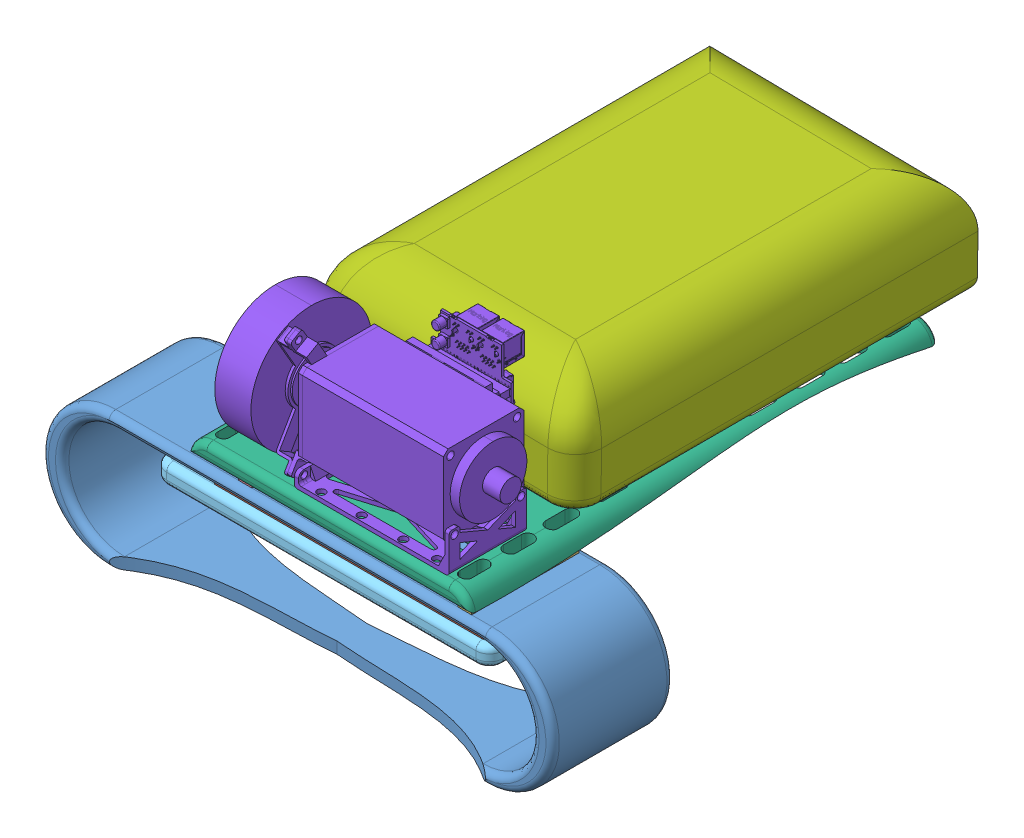
SolidWorks assembly Final_Assembly_Harness_2, configuration Default. Lengths in mm.
Overall size (380 213.95 399.05).
8 component instances, 8 part files, 22 mates.
Components (placement in the parent):
- 2. Belt-1: 2. Belt [Default] at (17.8971 161.4161 353.1185) size (380 100 91.64)
- 3. carbon fiber plate-1: 3. carbon fiber plate [Default] at (191.2898 202.9115 308.1185) x (1 0 0) z (0 -1 0) size (200 80 3)
- 4. carbon attachement_1-1: 4. carbon attachement_1 [Default] at (277.5835 211.4161 308.1185) x (1 0 0) z (0 1 0) size (10 80 3)
- 5. carbon attachement_2-1: 5. carbon attachement_2 [Default] at (114.2606 211.4161 308.1185) x (1 0 0) z (0 1 0) size (10 80 3)
- 6. Vibration absorbing material-1: 6. Vibration absorbing material [Default] at (175.8547 199.9115 308.1747) x (1 0 0) z (0 -1 0) size (250 90 15)
- 8. MOLLE_Back_support-1: 8. MOLLE_Back_support [Default] at (180.4669 227.9328 2.952) size (210.93 23.15 350)
- 1. Laptop Bag-3: 1. Laptop Bag [Default] at (176.1619 225.9574 115.5741) x (0 0 1) z (0.01497 0.999888 0) size (300 200 80)
- 9. motor_controller-1: 9. motor_controller [Default] at (80.7545 206.8549 332.7101) x (0 -1 0) z (1 0 0) size (99.44 114.56 175.11)
Mates (geometry in assembly coordinates):
- Coincident1: coincident: plane of 2. Belt-1 through (24.5044 202.9115 263.1185) normal (0 -1 0); plane of 3. carbon fiber plate-1 through (191.2898 202.9115 308.1185) normal (0 1 0)
- Coincident2: coincident: line of 2. Belt-1 through (291.2898 202.9115 268.1185) axis (0 0 1); plane of 3. carbon fiber plate-1 through (291.2898 199.9115 348.1185) normal (1 0 0)
- Coincident3: coincident: line of 2. Belt-1 through (24.5044 202.9115 268.1185) axis (1 0 0); plane of 3. carbon fiber plate-1 through (91.2898 199.9115 268.1185) normal (0 0 -1)
- Coincident4: coincident: plane of 3. carbon fiber plate-1 through (191.2898 199.9115 308.1185) normal (0 -1 0); plane of 6. Vibration absorbing material-1 through (175.8547 199.9115 308.1747) normal (0 1 0)
- Coincident5: coincident: line of 2. Belt-1 through (24.5044 207.1638 263.1747) axis (1 0 0); plane of 6. Vibration absorbing material-1 through (50.8547 184.9115 263.1747) normal (0 0 -1)
- Lock1: lock: unknown of 2. Belt-1; unknown of 3. carbon fiber plate-1
- Lock3: lock: unknown of 3. carbon fiber plate-1; unknown of 6. Vibration absorbing material-1
- Coincident9: coincident: plane of 2. Belt-1 through (17.8971 211.4161 263.1185) normal (0 1 0); plane of 4. carbon attachement_1-1 through (277.5835 211.4161 308.1185) normal (0 -1 0)
- Coincident10: coincident: plane of 2. Belt-1 through (17.8971 211.4161 263.1185) normal (0 1 0); plane of 5. carbon attachement_2-1 through (114.2606 211.4161 308.1185) normal (0 -1 0)
- Coincident11: coincident: line of 2. Belt-1 through (297.8971 211.4161 268.1185) axis (-1 0 0); plane of 5. carbon attachement_2-1 through (109.2606 214.4161 268.1185) normal (0 0 -1)
- Coincident12: coincident: line of 2. Belt-1 through (297.8971 211.4161 268.1185) axis (-1 0 0); plane of 4. carbon attachement_1-1 through (272.5835 214.4161 268.1185) normal (0 0 -1)
- Lock4: lock: unknown of 2. Belt-1; unknown of 4. carbon attachement_1-1
- Lock5: lock: unknown of 2. Belt-1; unknown of 5. carbon attachement_2-1
- Coincident28: coincident: line of 4. carbon attachement_1-1 through (272.5835 214.4161 348.1185) axis (1 0 0); line of 8. MOLLE_Back_support-1 through (285.3906 214.4161 348.1185) axis (-1 0 0)
- Perpendicular3: perpendicular: line of 4. carbon attachement_1-1 through (282.5835 214.4161 348.1185) axis (0 -1 0); line of 8. MOLLE_Back_support-1 through (285.3906 214.4161 348.1185) axis (-1 0 0)
- Parallel11: parallel: plane of 5. carbon attachement_2-1 through (114.2606 214.4161 308.1185) normal (0 1 0); plane of 8. MOLLE_Back_support-1 through (90.4669 227.9328 352.952) normal (0 1 0)
- Lock7: lock: unknown of 5. carbon attachement_2-1; unknown of 8. MOLLE_Back_support-1
- Coincident40: coincident: line of 8. MOLLE_Back_support-1 through (86.172 227.3047 28.3901) axis (0 0 -1); line of 1. Laptop Bag-3 through (86.172 227.3047 245.5741) axis (0 0 -1)
- Lock12: lock: unknown of 8. MOLLE_Back_support-1; unknown of 1. Laptop Bag-3
- Tangent1: tangent: plane of 8. MOLLE_Back_support-1 through (90.4669 227.9328 352.952) normal (0 1 0); face of 9. motor_controller-1
- Tangent3: tangent: plane of 8. MOLLE_Back_support-1 through (266.172 187.9328 340.4963) normal (1 0 0); face of 9. motor_controller-1
- Lock13: lock: unknown of 8. MOLLE_Back_support-1; unknown of 9. motor_controller-1
